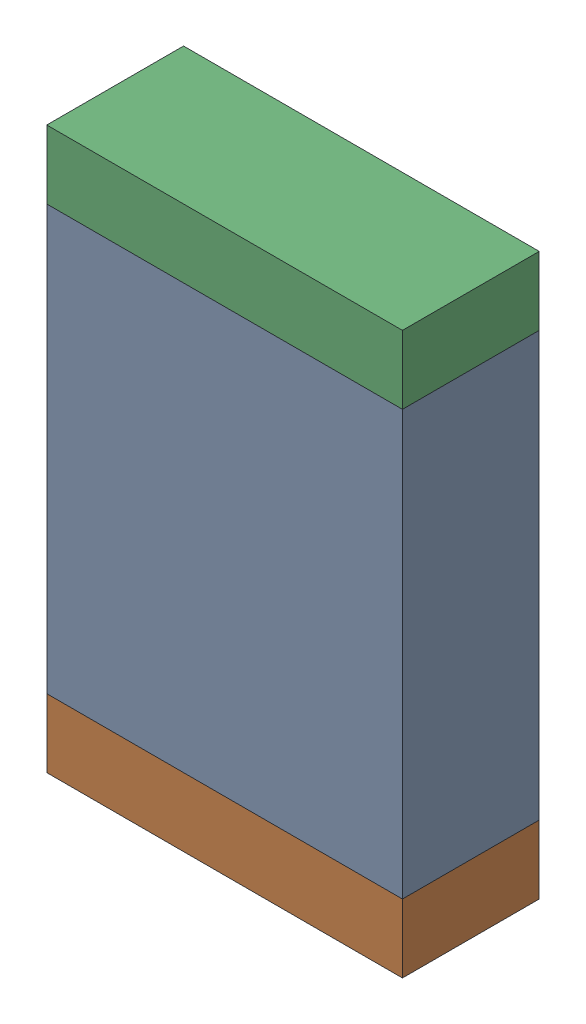
SolidWorks assembly L12, configuration Default. Lengths in mm.
Overall size (1.3 2.05 0.5).
6 component instances, 2 part files, 0 mates.
Components (placement in the parent):
- 836753008-1: 836753008 [Default] at (106.7 55.375 0) size (1.3 1.55 0.5)
  - Extruded_23-1: Extruded_23 [Default] at origin size (1.3 1.55 0.5)
- 836753264-1: 836753264 [Default] at (106.7 54.475 0) size (1.3 0.25 0.5)
  - Extruded_22-1: Extruded_22 [Default] at origin size (1.3 0.25 0.5)
- 836753264-2: 836753264 [Default] at (106.7 56.275 0) size (1.3 0.25 0.5)
  - Extruded_22-1: Extruded_22 [Default] at origin size (1.3 0.25 0.5)
